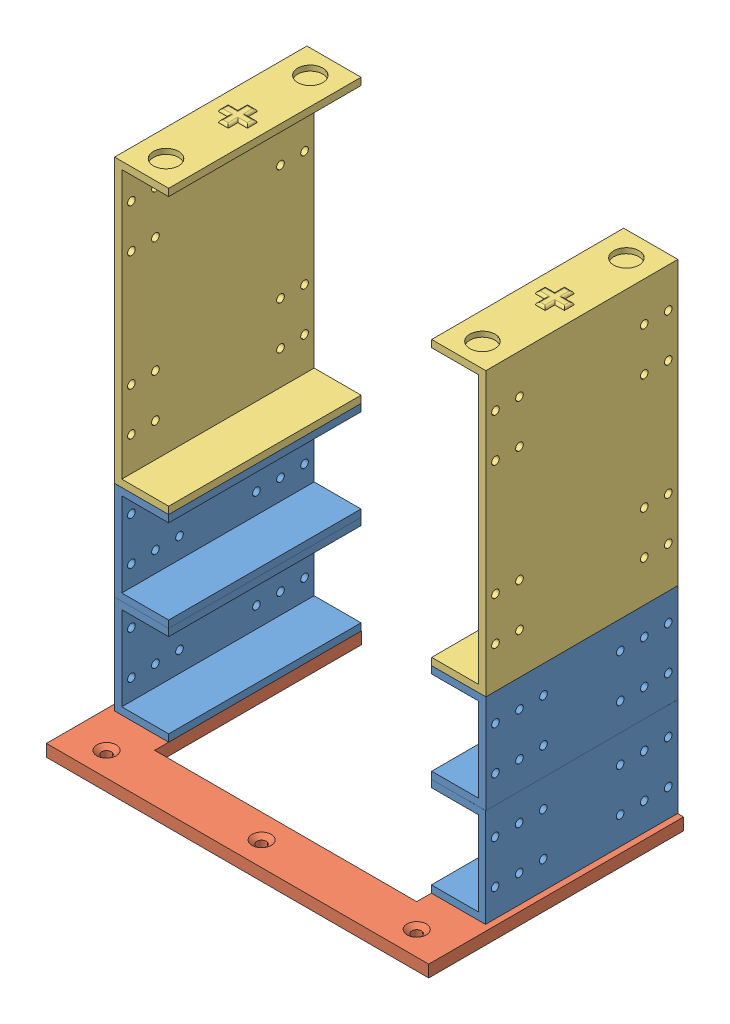
SolidWorks assembly Magnet Stack assembly, configuration Défaut. Lengths in mm.
Overall size (159 205.5 106.14).
7 component instances, 3 part files, 18 mates.
Components (placement in the parent):
- Magnet support 42mm-2: Magnet support 42mm [Défaut] at (75.3977 -26.9893 80.7882) x (-1 0 0) z (0 1 0) size (22.5 80 42)
- support-1: support [Défaut] at (-81.1023 -31.9893 186.9012) x (1 0 0) z (0 1 0) size (159 106 6)
- Magnet support 42mm-3: Magnet support 42mm [Défaut] at (-78.6023 -26.9893 161.0512) x (1 0 0) z (0 1 0) size (22.5 80 42)
- Magnet support 42mm-4: Magnet support 42mm [Défaut] at (75.3775 14.0107 80.7658) x (-0.999998 0 0.001987) z (0 1 0) size (22.5 80 42)
- Magnet support 42mm-5: Magnet support 42mm [Défaut] at (-78.6023 14.0107 161.0512) x (1 0 0) z (0 1 0) size (22.5 80 42)
- Magnet support GNS530-1: Magnet support GNS530 [Défaut] at (75.3775 55.0107 80.7658) x (-0.999998 0 0.001987) z (0 1 0) size (22.5 80 118.5)
- Magnet support GNS530-2: Magnet support GNS530 [Défaut] at (-78.6023 55.0107 161.0512) x (1 0 0) z (0 1 0) size (22.5 80 118.5)
Mates (geometry in assembly coordinates):
- Coïncidente34: coincident: line of Magnet support 42mm-2 through (75.3977 -26.9893 160.7882) axis (0 0 -1); plane of support-1 through (-81.1023 -26.9893 186.9012) normal (0 1 0)
- Parallèle25: parallel anti-aligned: plane of support-1 through (-81.1023 -26.9893 186.9012) normal (0 1 0); plane of Magnet support 42mm-3 through (-78.6023 -26.9893 161.0512) normal (0 -1 0)
- Coaxiale1: concentric aligned: circle of support-1; circle of Magnet support 42mm-3
- Parallèle26: parallel anti-aligned: plane of Magnet support 42mm-2 through (75.3977 14.0107 80.7882) normal (0 1 0); plane of Magnet support 42mm-4 through (75.3775 14.0107 80.7658) normal (0 -1 0)
- Parallèle27: parallel aligned: line of Magnet support 42mm-2 through (75.3977 14.0107 80.7882) axis (0 -1 0); line of Magnet support 42mm-4 through (75.3775 55.0107 80.7658) axis (0 -1 0)
- Coaxiale2: concentric anti-aligned: circle of Magnet support 42mm-2; circle of Magnet support 42mm-4
- Coïncidente37: coincident anti-aligned: plane of Magnet support 42mm-2 through (75.3977 14.0107 80.7882) normal (0 1 0); plane of Magnet support 42mm-4 through (75.3775 14.0107 80.7658) normal (0 -1 0)
- Parallèle28: parallel anti-aligned: plane of Magnet support 42mm-3 through (-75.6023 11.0107 161.0512) normal (1 0 0); plane of Magnet support 42mm-5 through (-78.6023 17.0107 161.0512) normal (-1 0 0)
- Parallèle29: parallel aligned: plane of Magnet support 42mm-3 through (-78.6023 -23.9893 81.0512) normal (0 0 -1); plane of Magnet support 42mm-5 through (-78.6023 17.0107 81.0512) normal (0 0 -1)
- Coaxiale3: concentric anti-aligned: circle of Magnet support 42mm-3; circle of Magnet support 42mm-5
- Coïncidente38: coincident anti-aligned: plane of Magnet support 42mm-3 through (-78.6023 14.0107 161.0512) normal (0 1 0); plane of Magnet support 42mm-5 through (-78.6023 14.0107 161.0512) normal (0 -1 0)
- Parallèle30: parallel aligned: plane of Magnet support 42mm-4 through (75.3775 17.0107 80.7658) normal (0.999998 0 -0.001987); plane of Magnet support GNS530-1 through (75.3775 58.0107 80.7658) normal (0.999998 0 -0.001987)
- Parallèle31: parallel aligned: plane of Magnet support 42mm-4 through (75.3775 17.0107 80.7658) normal (-0.001987 0 -0.999998); plane of Magnet support GNS530-1 through (75.3775 58.0107 80.7658) normal (-0.001987 0 -0.999998)
- Coaxiale4: concentric anti-aligned: circle of Magnet support 42mm-4; circle of Magnet support GNS530-1
- Coïncidente39: coincident anti-aligned: plane of Magnet support 42mm-4 through (75.3775 55.0107 80.7658) normal (0 1 0); plane of Magnet support GNS530-1 through (75.3775 55.0107 80.7658) normal (0 -1 0)
- Coaxiale5: concentric anti-aligned: circle of Magnet support 42mm-5; circle of Magnet support GNS530-2
- Coïncidente40: coincident anti-aligned: plane of Magnet support 42mm-5 through (-78.6023 55.0107 161.0512) normal (0 1 0); plane of Magnet support GNS530-2 through (-78.6023 55.0107 161.0512) normal (0 -1 0)
- Coïncidente41: coincident anti-aligned: plane of support-1 through (-81.1023 -26.9893 186.9012) normal (0 1 0); plane of Magnet support 42mm-3 through (-78.6023 -26.9893 161.0512) normal (0 -1 0)
